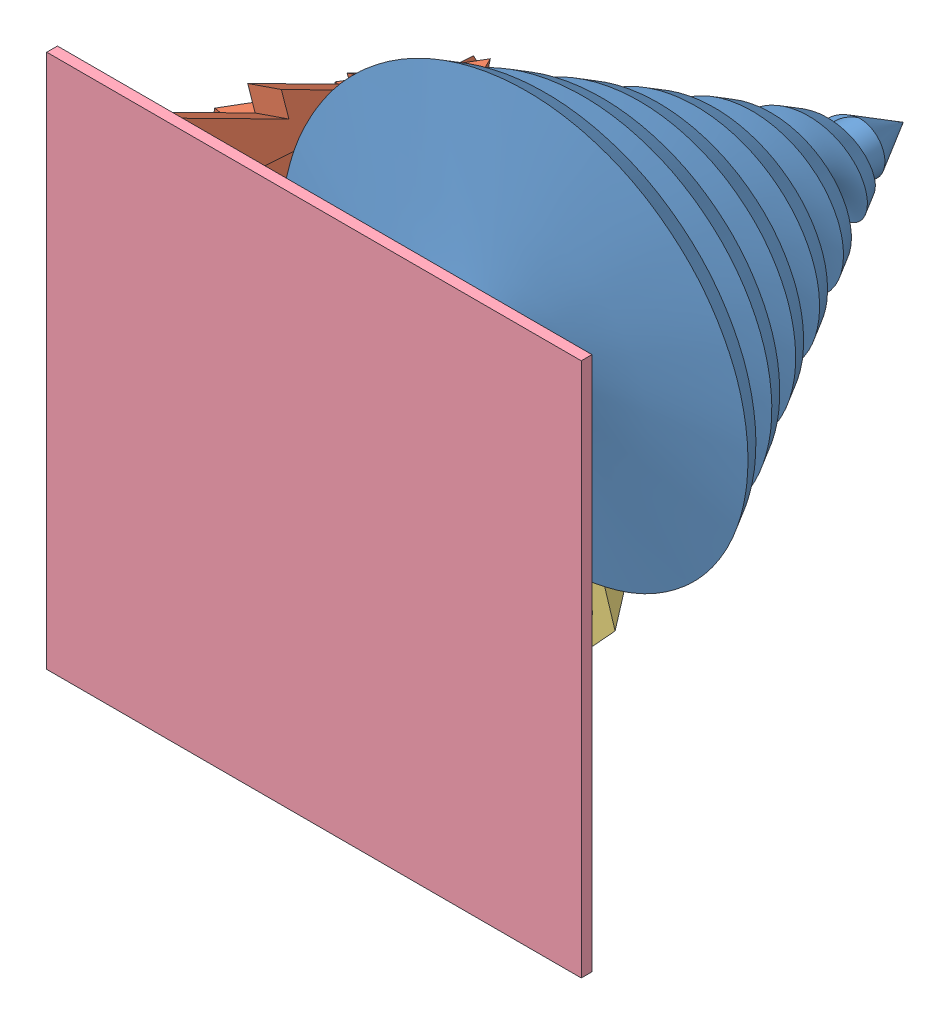
SolidWorks assembly Assemblage1, configuration Défaut. Lengths in mm.
Overall size (199.54 220.6 125.67).
4 component instances, 4 part files, 6 mates.
Components (placement in the parent):
- Sapin de noel(1)-1: Sapin de noel(1) [Défaut] at origin size (131.65 129.24 122.67)
- Sapin de Noël Frédéric-1: Sapin de Noël Frédéric [Défaut] at (-94.2578 -23.5831 -17.0751) x (-0.656348 -0.754458 0) z (0 0 -1) size (60 56.96 100)
- sapin noel-1: sapin noel [Défaut] at (-47.5465 -93.6974 -37.0751) x (0.954009 0.299777 0) z (0 0 1) size (86.6 100 117)
- Pièce2^Assemblage1-1: Pièce2^Assemblage1 [Défaut] at (0 0 -17.0751) size (150 150 3) (virtual)
Mates (geometry in assembly coordinates):
- Sur place1: in place: plane of Sapin de noel(1)-1 through (-0.0731 1.1614 -17.0751) normal (0 0 1); plane of Pièce2^Assemblage1-1 through (0 0 -17.0751) normal (0 0 1); moOrthogonalPlaneRef_w of Sapin de noel(1)-1 through (-0.0731 1.1614 -17.0751) normal (0 0 1); plane of Pièce2^Assemblage1-1 through (0 0 -17.0751) normal (0 1 0); plane of Sapin de noel(1)-1 through (-0.0731 1.1614 -17.0751) normal (0 0 1); plane of Pièce2^Assemblage1-1 through (0 0 -17.0751) normal (1 0 0); plane of Sapin de noel(1)-1 through (-0.0731 1.1614 -17.0751) normal (0 0 1); unknown of Pièce2^Assemblage1-1
- Coïncidente1: coincident aligned: plane of Sapin de noel(1)-1; plane of Pièce2^Assemblage1-1
- Coïncidente2: coincident aligned: moOrthogonalPlaneRef_w of Sapin de noel(1)-1 through (0 0 -17.0751) normal (0 1 0); plane of Pièce2^Assemblage1-1 through (0 0 -17.0751) normal (0 1 0)
- Coïncidente3: coincident anti-aligned: moOrthogonalPlaneRef_w of Sapin de noel(1)-1 through (0 0 -17.0751) normal (-1 0 0); plane of Pièce2^Assemblage1-1 through (0 0 -17.0751) normal (1 0 0)
- Coïncidente4: coincident anti-aligned: plane of Sapin de Noël Frédéric-1 through (-94.2578 -23.5831 -17.0751) normal (0 0 1); plane of Pièce2^Assemblage1-1 through (0 0 -17.0751) normal (0 0 -1)
- Coïncidente5: coincident anti-aligned: plane of sapin noel-1 through (-47.5465 -93.6974 -17.0751) normal (0 0 1); plane of Pièce2^Assemblage1-1 through (0 0 -17.0751) normal (0 0 -1)
